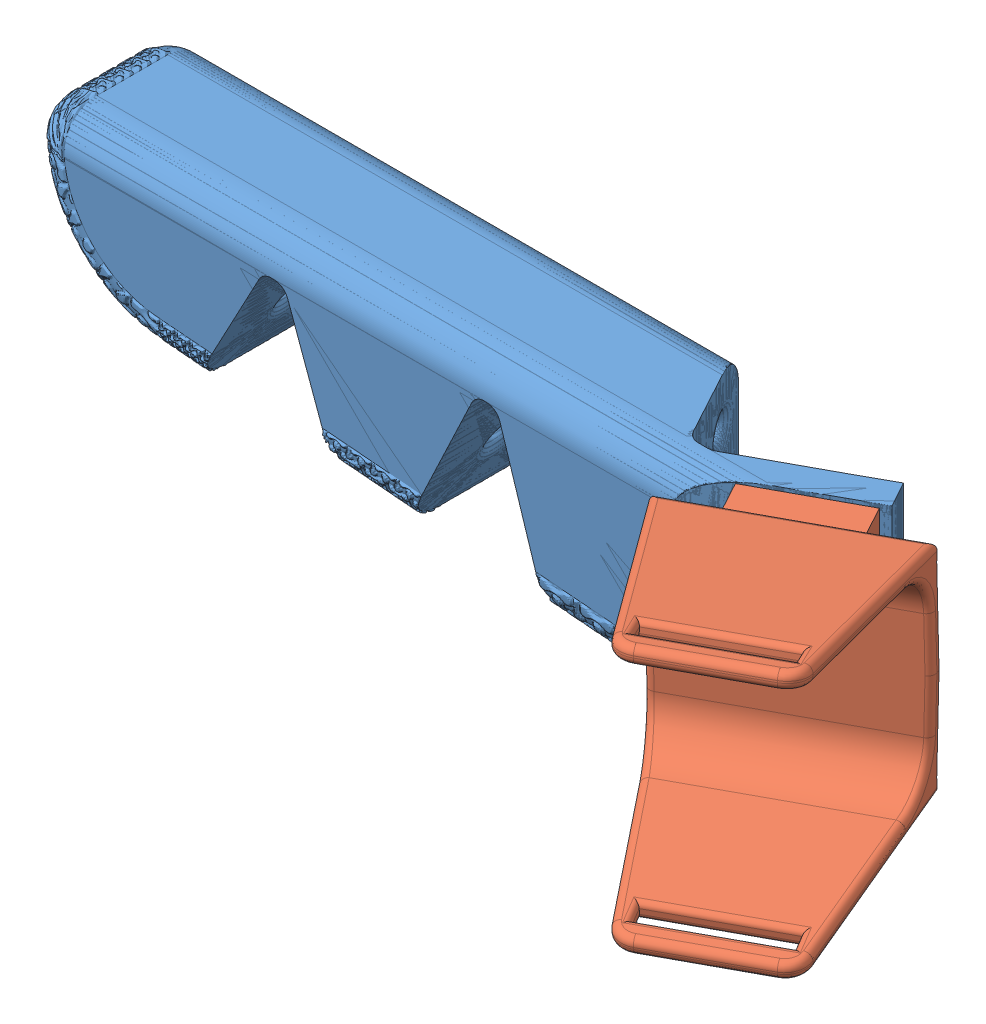
SolidWorks assembly Assem1, configuration Default. Lengths in mm.
Overall size (133.95 37.66 52.03).
2 component instances, 2 part files, 3 mates.
Components (placement in the parent):
- third thumb v1-1: third thumb v1 [Default] at (76.7093 43.2346 76.9797) size (111.29 30.78 20.92)
- thumb base-1: thumb base [Default] at (82.9632 44.7229 81.7858) x (0 -1 0) z (-0.476688 0 -0.879073) size (37.66 30.48 35.83)
Mates (geometry in assembly coordinates):
- Coincident4: coincident anti-aligned: plane of third thumb v1-1 through (62.8959 43.2346 86.9797) normal (0.476688 0 0.879073); plane of thumb base-1 through (80.5798 44.7229 77.3904) normal (-0.476688 0 -0.879073)
- Coincident5: coincident anti-aligned: plane of third thumb v1-1 through (79.402 69.8831 78.0291) normal (0.725743 0 -0.687966); plane of thumb base-1 through (82.9632 44.7229 81.7858) normal (-0.725743 0 0.687966)
- Coincident7: coincident anti-aligned: plane of third thumb v1-1 through (79.402 69.8831 78.0291) normal (-0.123376 0.965926 -0.227521); plane of thumb base-1 through (82.9632 71.2229 81.7858) normal (0.123376 -0.965926 0.227521)
